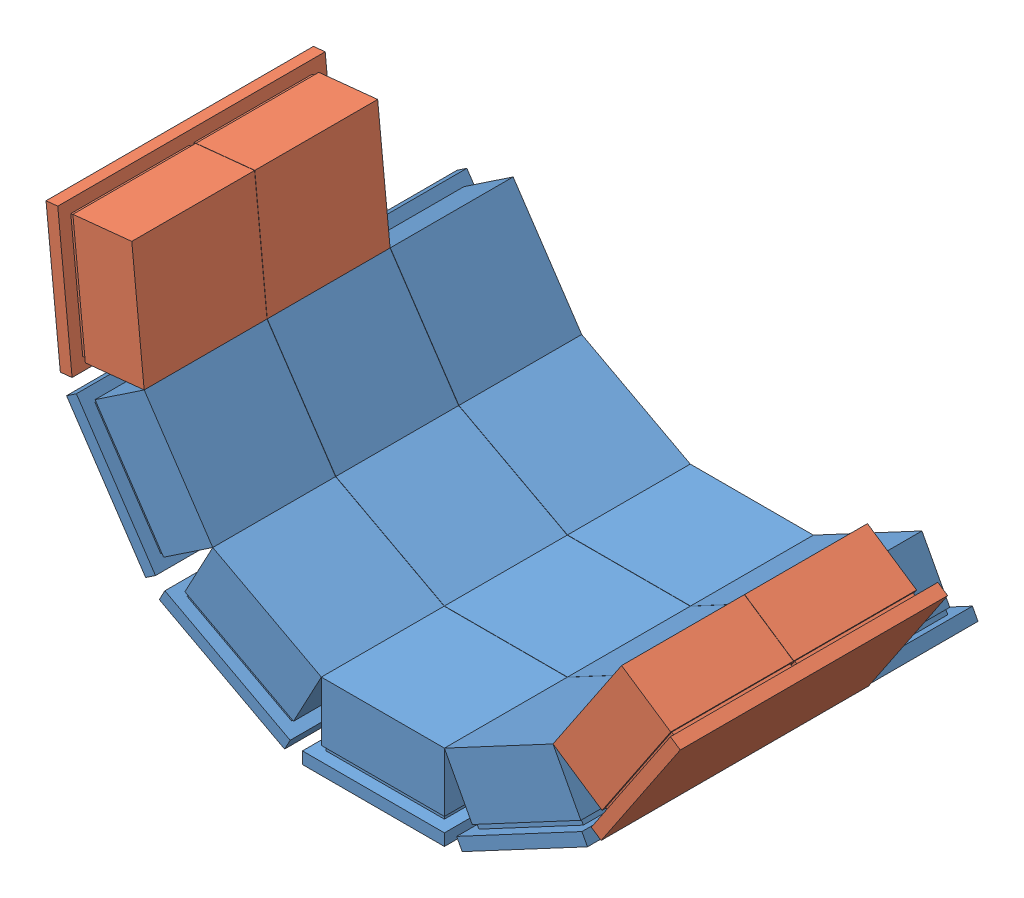
SolidWorks assembly SideDetector, configuration Default. Lengths in mm.
Overall size (268 155.36 165).
6 component instances, 2 part files, 15 mates.
Components (placement in the parent):
- 52mmX4-1: 52mmX4 [Default] at (-99.1405 6.5957 36.9639) size (60 32 165)
- 52mmX4-2: 52mmX4 [Default] at (-35.1412 22.594 36.9639) x (0.882373 0.47055 0) z (0 0 1) size (60 32 165)
- 52mmX4-3: 52mmX4 [Default] at (-163.1399 22.594 36.9639) x (0.882373 -0.47055 0) z (0 0 1) size (60 32 165)
- 52mmX4-4: 52mmX4 [Default] at (-212.0831 66.8254 36.9639) x (0.557166 -0.830401 0) z (0 0 1) size (60 32 165)
- 52mmX3-1: 52mmX3 [Default] at (-234.4563 128.8843 62.9639) x (0.100883 -0.994898 0) z (0 0 1) size (60 32 113)
- 52mmX3-2: 52mmX3 [Default] at (13.802 66.8254 62.9639) x (0.557166 0.830401 0) z (0 0 1) size (60 32 113)
Mates (geometry in assembly coordinates):
- Coincident1: coincident anti-aligned: line of 52mmX4-3 through (-171.024 63.0643 63.5639) axis (0 0 1); line of 52mmX4-4 through (-171.024 63.0643 115.4639) axis (0 0 -1)
- Coincident2: coincident: point of 52mmX4-3; point of 52mmX4-4
- Angle1: planar angle = 3.631507 rad anti-aligned: line of 52mmX4-4 through (-199.9966 106.2452 115.4639) axis (0.557166 -0.830401 0); line of 52mmX4-3 through (-171.024 63.0643 115.4639) axis (0.882373 -0.47055 0)
- Coincident4: coincident anti-aligned: line of 52mmX4-1 through (-125.1405 38.5957 63.5639) axis (0 0 1); line of 52mmX4-3 through (-125.1405 38.5957 115.4639) axis (0 0 -1)
- Coincident5: coincident: point of 52mmX4-1; point of 52mmX4-3
- Angle2: planar angle = 3.631507 rad anti-aligned: line of 52mmX4-3 through (-171.024 63.0643 115.4639) axis (0.882373 -0.47055 0); line of 52mmX4-1 through (-125.1405 38.5957 115.4639) axis (1 0 0)
- Coincident7: coincident anti-aligned: line of 52mmX4-1 through (-73.1405 38.5957 115.4639) axis (0 0 -1); line of 52mmX4-2 through (-73.1405 38.5957 63.5639) axis (0 0 1)
- Coincident8: coincident: point of 52mmX4-1; point of 52mmX4-2
- Angle3: planar angle = 3.631507 rad anti-aligned: line of 52mmX4-1 through (-125.1405 38.5957 115.4639) axis (1 0 0); line of 52mmX4-2 through (-73.1405 38.5957 115.4639) axis (0.882373 0.47055 0)
- Coincident10: coincident anti-aligned: line of 52mmX4-4 through (-199.9966 106.2452 63.5639) axis (0 0 1); line of 52mmX3-1 through (-199.9966 106.2452 115.4639) axis (0 0 -1)
- Angle4: planar angle = 3.631507 rad anti-aligned: line of 52mmX3-1 through (-205.2425 157.9799 115.4639) axis (0.100883 -0.994898 0); line of 52mmX4-4 through (-199.9966 106.2452 115.4639) axis (0.557166 -0.830401 0)
- Coincident12: coincident: point of 52mmX4-4; point of 52mmX3-1
- Coincident13: coincident anti-aligned: line of 52mmX4-2 through (-27.2571 63.0643 115.4639) axis (0 0 -1); line of 52mmX3-2 through (-27.2571 63.0643 63.5639) axis (0 0 1)
- Angle5: planar angle = 3.631507 rad anti-aligned: line of 52mmX3-2 through (-27.2571 63.0643 115.4639) axis (0.557166 0.830401 0); line of 52mmX4-2 through (-73.1405 38.5957 115.4639) axis (0.882373 0.47055 0)
- Coincident15: coincident: point of 52mmX4-2; point of 52mmX3-2
